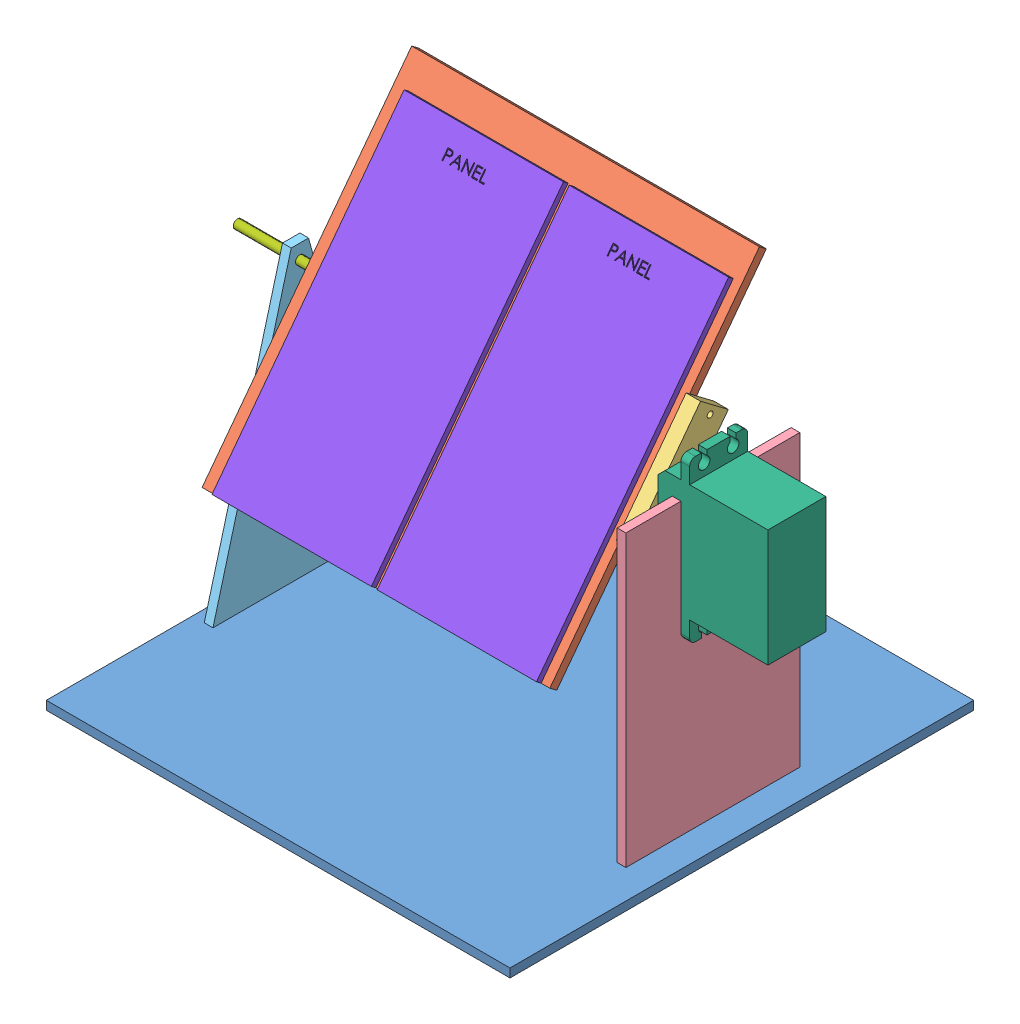
SolidWorks assembly ENSAMBLAJE FINAL, configuration Predeterminado. Lengths in mm.
Overall size (193 149.99 160).
9 component instances, 8 part files, 23 mates.
Components (placement in the parent):
- BASE-1: BASE [Predeterminado] at (-1.0418 -32.885 160) size (160 3 160)
- panel_pieza3-1: panel_pieza3 [Predeterminado] at (-6.5418 67.4189 162.197) x (1 0 0) z (0 -0.797999 0.602659) size (120 3 120)
- pinza_servo_Pieza6-1: pinza_servo_Pieza6 [Predeterminado] at (53.4582 66.515 161) x (1 0 0) z (0 -0.797999 0.602659) size (5 12 40)
- Soporte_derecho_Pieza2-1: Soporte_derecho_Pieza2 [Predeterminado] at (65.9582 20.115 160) size (3 100 60)
- Soporte_izquierdo_Pieza2-1: Soporte_izquierdo_Pieza2 [Predeterminado] at (-75.5418 -28.485 161) size (3 100 60)
- Pieza3 Servo sg5010-1: Pieza3 Servo sg5010 [Predeterminado] at (79.9582 56.315 171) x (0 1 0) z (0 0 1) size (55.4 43 28.4)
- pasador_Pieza4.4-1: pasador_Pieza4.4 [Predeterminado] at (-94.0418 66.515 161) x (1 0 0) z (0 -0.999985 -0.005555) size (150 3 3)
- PANELE-1: PANELE [Predeterminado] at (-34.0418 65.2369 167.6043) x (1 0 0) z (0 -0.797999 0.602659) size (55 2 110)
- PANELE-2: PANELE [Predeterminado] at (22.9582 65.2369 167.6043) x (1 0 0) z (0 -0.797999 0.602659) size (55 2 110)
Mates (geometry in assembly coordinates):
- Coincidente1: coincident anti-aligned: plane of BASE-1 through (-1.0418 -29.885 160) normal (0 1 0); plane of Soporte_derecho_Pieza2-1 through (68.9582 -29.885 130) normal (0 -1 0)
- Coincidente2: coincident anti-aligned: plane of Soporte_derecho_Pieza2-1 through (68.9582 20.115 160) normal (1 0 0); plane of Pieza3 Servo sg5010-1 through (68.9582 28.615 171) normal (-1 0 0)
- Distancia1: distance = 1 mm anti-aligned: plane of Pieza3 Servo sg5010-1 through (79.9582 56.315 151) normal (0 0 -1); plane of Soporte_derecho_Pieza2-1 through (65.9582 70.115 150) normal (0 0 1)
- Concéntrica1: concentric aligned: cylinder of pinza_servo_Pieza6-1 through (53.4582 66.515 161) axis (1 0 0) radius 3; cylinder of Pieza3 Servo sg5010-1 through (55.9582 66.515 161) axis (1 0 0) radius 3
- Coincidente5: coincident anti-aligned: plane of Soporte_derecho_Pieza2-1 through (65.9582 36.115 160) normal (0 1 0); plane of Pieza3 Servo sg5010-1 through (98.9582 36.115 151) normal (0 -1 0)
- Distancia4: distance = 2.5 mm aligned: plane of Pieza3 Servo sg5010-1 through (55.9582 66.515 161) normal (-1 0 0); plane of pinza_servo_Pieza6-1 through (53.4582 66.515 161) normal (-1 0 0)
- Concéntrica3: concentric anti-aligned: cylinder of pinza_servo_Pieza6-1 through (53.4582 66.515 161) axis (1 0 0) radius 3; cylinder of pasador_Pieza4.4-1 through (55.9582 66.515 161) axis (-1 0 0) radius 1.5
- Coincidente10: coincident anti-aligned: plane of Pieza3 Servo sg5010-1 through (55.9582 66.515 161) normal (-1 0 0); plane of pasador_Pieza4.4-1 through (55.9582 66.515 161) normal (1 0 0)
- Coincidente11: coincident anti-aligned: plane of panel_pieza3-1 through (53.4582 38.2541 214.1185) normal (1 0 0); plane of pinza_servo_Pieza6-1 through (53.4582 66.515 161) normal (-1 0 0)
- Distancia7: distance = 40 mm aligned: plane of panel_pieza3-1; plane of pinza_servo_Pieza6-1
- Tangente5: tangent anti-aligned: plane of panel_pieza3-1; cylinder of pasador_Pieza4.4-1 through (55.9582 66.515 161) axis (-1 0 0) radius 1.5
- Paralelo2: parallel anti-aligned: cylinder of Soporte_izquierdo_Pieza2-1 through (-75.5418 66.515 161) axis (1 0 0) radius 1.5; cylinder of pasador_Pieza4.4-1 through (55.9582 66.515 161) axis (-1 0 0) radius 1.5
- Concéntrica9: concentric anti-aligned: cylinder of Soporte_izquierdo_Pieza2-1 through (-75.5418 66.515 161) axis (1 0 0) radius 1.5; cylinder of pasador_Pieza4.4-1 through (55.9582 66.515 161) axis (-1 0 0) radius 1.5
- Distancia10: distance = 50 mm aligned: plane of BASE-1 through (78.9582 -29.885 240) normal (0 0 1); plane of Soporte_derecho_Pieza2-1 through (68.9582 -29.885 190) normal (0 0 1)
- Distancia11: distance = 6 mm anti-aligned: plane of Soporte_izquierdo_Pieza2-1 through (-72.5418 -28.485 161) normal (1 0 0); plane of panel_pieza3-1 through (-66.5418 38.2541 214.1185) normal (-1 0 0)
- Distancia12: distance = 10 mm aligned: plane of Soporte_derecho_Pieza2-1 through (68.9582 20.115 160) normal (1 0 0); plane of BASE-1 through (78.9582 -29.885 80) normal (1 0 0)
- Paralelo6: parallel anti-aligned: plane of BASE-1 through (-1.0418 -29.885 160) normal (0 1 0); plane of Soporte_izquierdo_Pieza2-1 through (-72.5418 -28.485 161) normal (0 -1 0)
- Coincidente20: coincident anti-aligned: plane of panel_pieza3-1; plane of PANELE-1
- Coincidente21: coincident aligned: plane of panel_pieza3-1; plane of PANELE-1
- Distancia13: distance = 5 mm aligned: plane of panel_pieza3-1 through (-66.5418 38.2541 214.1185) normal (-1 0 0); plane of PANELE-1 through (-61.5418 39.9445 215.1873) normal (-1 0 0)
- Coincidente23: coincident anti-aligned: plane of panel_pieza3-1; plane of PANELE-2
- Coincidente24: coincident aligned: plane of panel_pieza3-1; plane of PANELE-2
- Distancia14: distance = 3 mm aligned: plane of panel_pieza3-1 through (53.4582 38.2541 214.1185) normal (1 0 0); plane of PANELE-2 through (50.4582 39.9445 215.1873) normal (1 0 0)
